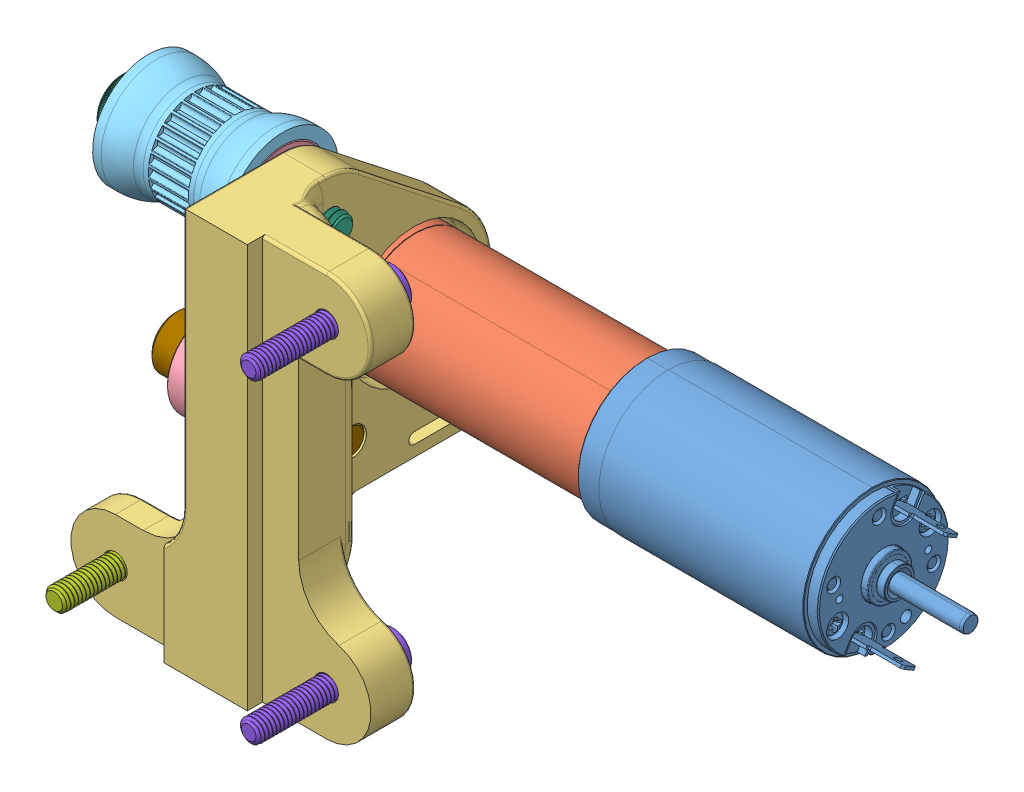
SolidWorks assembly teststand_base_belt_motorholder, configuration Default. Lengths in mm.
Overall size (137.75 75.99 60.04).
14 component instances, 10 part files, 28 mates.
Components (placement in the parent):
- 302534_RE25_GB_20W_KL_2WE-1: 302534_RE25_GB_20W_KL_2WE [Default] at (12.0527 46.5962 55.497) size (78.61 25 25)
- 370792_GP22HP_3_4NM_4ST_KL-1: 370792_GP22HP_3_4NM_4ST_KL [Default] at (-33.4373 46.5962 55.497) x (1 0 0) z (0 -0.499998 0.866026) size (62 22 22)
- teststand_motormount-1: teststand_motormount [Default] at (-33.4373 46.5962 86.297) x (1 0 0) z (0 1 0) size (54 47.59 74.56)
- 60355K430_BALL BEARING-3: 60355K430_BALL BEARING [60355K43] at (-40.4265 66.5962 70.647) x (0 0 1) z (-1 0 0) size (15.88 15.88 4.98)
- 60355K430_BALL BEARING-4: 60355K430_BALL BEARING [60355K43] at (-59.6549 66.5962 70.647) x (0 0 1) z (-1 0 0) size (15.88 15.88 4.98)
- teststand_tensioner_pulley_clamp-2: teststand_tensioner_pulley_clamp [bigger] at (-35.6359 56.3377 65.1795) x (0 -0.103926 0.994585) z (-1 0 0) size (20 20 24.25)
- 91259A542_ALLOY STEEL SHOULDER SCREW-1: 91259A542_ALLOY STEEL SHOULDER SCREW [91259A542] at (-66.9066 66.5962 70.647) x (0 0 1) z (-1 0 0) size (9.53 9.53 40.31)
- 91294A194_BLACK ALLOY STEEL FLAT-HEAD SOCKET CAP SCREW-1: 91294A194_BLACK ALLOY STEEL FLAT-HEAD SOCKET CAP SCREW [91294A194] at (-52.4373 9.5962 81.297) x (-0.862432 -0.506173 0) z (0 0 -1) size (8 8 16.42)
- 91290A170_BLACK-OXIDE CLASS 12.9 SOCKET HEAD CAP SCREW-1: 91290A170_BLACK-OXIDE CLASS 12.9 SOCKET HEAD CAP SCREW [91290A170] at (-14.4373 9.5962 100.297) size (7 7 26.39)
- 91251A542_BLACK-OXIDE ALLOY STEEL SOCKET HEAD CAP SCREW-1: 91251A542_BLACK-OXIDE ALLOY STEEL SOCKET HEAD CAP SCREW [91251A542] at (-29.5941 30.5962 66.647) x (0 0 -1) z (1 0 0) size (9.53 9.53 32.53)
- teststand_spacer-1: teststand_spacer [Default] at (-45.0373 30.5962 66.647) x (0 -1 0) z (0 0 1) size (12.5 7.6 12.5)
- 60355K430_BALL BEARING-5: 60355K430_BALL BEARING [60355K43] at (-52.5049 30.5962 66.647) x (0 0 1) z (-1 0 0) size (15.88 15.88 4.98)
- 60355K430_BALL BEARING-6: 60355K430_BALL BEARING [60355K43] at (-47.5265 30.5962 66.647) x (0 0 1) z (-1 0 0) size (15.88 15.88 4.98)
- 91290A170_BLACK-OXIDE CLASS 12.9 SOCKET HEAD CAP SCREW-2: 91290A170_BLACK-OXIDE CLASS 12.9 SOCKET HEAD CAP SCREW [91290A170] at (-14.4373 66.2462 100.297) x (0.968665 -0.248372 0) z (0 0 1) size (7 7 26.39)
Mates (geometry in assembly coordinates):
- Concentric1: concentric: cylinder of 302534_RE25_GB_20W_KL_2WE-1 through (10.2392 46.5962 55.497) axis (1 0 0) radius 12.5; cylinder of 370792_GP22HP_3_4NM_4ST_KL-1 through (-49.7373 46.5962 55.497) axis (1 0 0) radius 11
- Coincident1: coincident: plane of 302534_RE25_GB_20W_KL_2WE-1 through (12.2627 46.5962 55.497) normal (-1 0 0); plane of 370792_GP22HP_3_4NM_4ST_KL-1 through (12.2627 46.5962 55.497) normal (1 0 0)
- Concentric2: concentric: cylinder of 370792_GP22HP_3_4NM_4ST_KL-1 through (-49.7373 46.5962 55.497) axis (1 0 0) radius 11; cylinder of teststand_motormount-1 through (-6.4373 46.5962 55.497) axis (-1 0 0) radius 12
- Concentric3: concentric: cylinder of 370792_GP22HP_3_4NM_4ST_KL-1 through (-28.7326 54.8234 60.247) axis (-1 0 0) radius 0.8; cylinder of teststand_motormount-1 through (-29.4373 54.8234 60.247) axis (-1 0 0) radius 1.25
- Coincident2: coincident: plane of 370792_GP22HP_3_4NM_4ST_KL-1 through (-33.4373 46.5962 55.497) normal (-1 0 0); plane of teststand_motormount-1 through (-33.4373 46.5962 55.497) normal (1 0 0)
- Coincident5: coincident: plane of 60355K430_BALL BEARING-3 through (-42.9157 74.2848 70.647) normal (-1 0 0); plane of teststand_tensioner_pulley_clamp-2 through (-42.9157 66.5962 70.647) normal (1 0 0)
- Coincident6: coincident: plane of 60355K430_BALL BEARING-4 through (-57.1657 74.2848 70.647) normal (1 0 0); plane of teststand_tensioner_pulley_clamp-2 through (-57.1657 66.5962 70.647) normal (-1 0 0)
- Concentric6: concentric: cylinder of 60355K430_BALL BEARING-4 through (-62.1441 66.5962 70.647) axis (-1 0 0) radius 7.9375; cylinder of teststand_tensioner_pulley_clamp-2 through (-62.1657 66.5962 70.647) axis (1 0 0) radius 7.95
- Concentric7: concentric: cylinder of 60355K430_BALL BEARING-3 through (-42.9157 66.5962 70.647) axis (-1 0 0) radius 7.9375; cylinder of teststand_tensioner_pulley_clamp-2 through (-37.9157 66.5962 70.647) axis (-1 0 0) radius 7.95
- Coincident7: coincident: plane of teststand_motormount-1 through (-37.9373 66.5962 70.647) normal (-1 0 0); plane of 60355K430_BALL BEARING-3 through (-37.9373 70.0201 70.647) normal (1 0 0)
- Concentric8: concentric: cylinder of teststand_motormount-1 through (-29.4373 66.5962 70.647) axis (-1 0 0) radius 1.8923; cylinder of 60355K430_BALL BEARING-4 through (-62.1441 66.5962 70.647) axis (-1 0 0) radius 3.175
- Coincident8: coincident: plane of teststand_motormount-1 through (-45.4373 1.5962 81.297) normal (0 0 -1); plane of 91294A194_BLACK ALLOY STEEL FLAT-HEAD SOCKET CAP SCREW-1 through (-51.425 7.8713 81.297) normal (0 0 -1)
- Concentric9: concentric: cylinder of teststand_motormount-1 through (-52.4373 9.5962 78.297) axis (0 0 1) radius 2.15; cylinder of 91294A194_BLACK ALLOY STEEL FLAT-HEAD SOCKET CAP SCREW-1 through (-52.4373 9.5962 81.297) axis (0 0 -1) radius 4
- Concentric11: concentric: cylinder of teststand_motormount-1 through (-14.4373 9.5962 78.297) axis (0 0 1) radius 2.15; cylinder of 91290A170_BLACK-OXIDE CLASS 12.9 SOCKET HEAD CAP SCREW-1 through (-14.4373 9.5962 74.297) axis (0 0 1) radius 3.5
- Coincident9: coincident: plane of teststand_motormount-1 through (-14.4373 9.5962 78.297) normal (0 0 -1); plane of 91290A170_BLACK-OXIDE CLASS 12.9 SOCKET HEAD CAP SCREW-1 through (-14.4373 9.5962 78.297) normal (0 0 1)
- Coincident10: coincident: plane of 60355K430_BALL BEARING-4 through (-62.1441 71.6735 70.647) normal (-1 0 0); plane of 91259A542_ALLOY STEEL SHOULDER SCREW-1 through (-62.1441 61.8337 70.647) normal (1 0 0)
- Concentric12: concentric: cylinder of 60355K430_BALL BEARING-4 through (-62.1441 66.5962 70.647) axis (-1 0 0) radius 3.175; cylinder of 91259A542_ALLOY STEEL SHOULDER SCREW-1 through (-27.2191 66.5962 70.647) axis (1 0 0) radius 3.175
- Coincident11: coincident: plane of teststand_motormount-1 through (-37.4373 46.5962 55.497) normal (-1 0 0); plane of teststand_spacer-1 through (-37.4373 30.5962 66.647) normal (1 0 0)
- Concentric13: concentric: cylinder of teststand_spacer-1 through (-37.4373 30.5962 66.647) axis (-1 0 0) radius 3.25; cylinder of teststand_motormount-1 through (-29.4373 30.5962 66.647) axis (-1 0 0) radius 2.54
- Concentric14: concentric: cylinder of 60355K430_BALL BEARING-5 through (-54.9941 30.5962 66.647) axis (-1 0 0) radius 3.175; cylinder of 60355K430_BALL BEARING-6 through (-50.0157 30.5962 66.647) axis (-1 0 0) radius 3.175
- Coincident12: coincident: plane of 60355K430_BALL BEARING-5 through (-50.0157 34.0201 66.647) normal (1 0 0); plane of 60355K430_BALL BEARING-6 through (-50.0157 35.6735 66.647) normal (-1 0 0)
- Coincident13: coincident: plane of teststand_spacer-1 through (-45.0373 30.5962 66.647) normal (-1 0 0); plane of 60355K430_BALL BEARING-6 through (-45.0373 34.0201 66.647) normal (1 0 0)
- Concentric15: concentric: cylinder of teststand_spacer-1 through (-37.4373 30.5962 66.647) axis (-1 0 0) radius 3.25; cylinder of 60355K430_BALL BEARING-6 through (-50.0157 30.5962 66.647) axis (-1 0 0) radius 3.175
- Coincident14: coincident: plane of 91251A542_BLACK-OXIDE ALLOY STEEL SOCKET HEAD CAP SCREW-1 through (-54.9941 30.5962 66.647) normal (1 0 0); plane of 60355K430_BALL BEARING-5 through (-54.9941 35.6735 66.647) normal (-1 0 0)
- Concentric16: concentric: cylinder of 91251A542_BLACK-OXIDE ALLOY STEEL SOCKET HEAD CAP SCREW-1 through (-61.3441 30.5962 66.647) axis (1 0 0) radius 4.7625; cylinder of 60355K430_BALL BEARING-5 through (-54.9941 30.5962 66.647) axis (-1 0 0) radius 3.175
- Concentric17: concentric: cylinder of teststand_motormount-1 through (-14.4373 66.2462 57.6815) axis (0 0 1) radius 2.15; cylinder of 91290A170_BLACK-OXIDE CLASS 12.9 SOCKET HEAD CAP SCREW-2 through (-14.4373 66.2462 74.297) axis (0 0 1) radius 3.5
- Parallel1: parallel: plane of teststand_motormount-1 through (-33.4373 46.5962 86.297) normal (0 0 -1); plane of assembly through (0 0 0) normal (0 0 1)
- Coincident15: coincident: plane of teststand_motormount-1 through (-14.4373 9.5962 78.297) normal (0 0 -1); plane of 91290A170_BLACK-OXIDE CLASS 12.9 SOCKET HEAD CAP SCREW-2 through (-14.4373 66.2462 78.297) normal (0 0 1)
